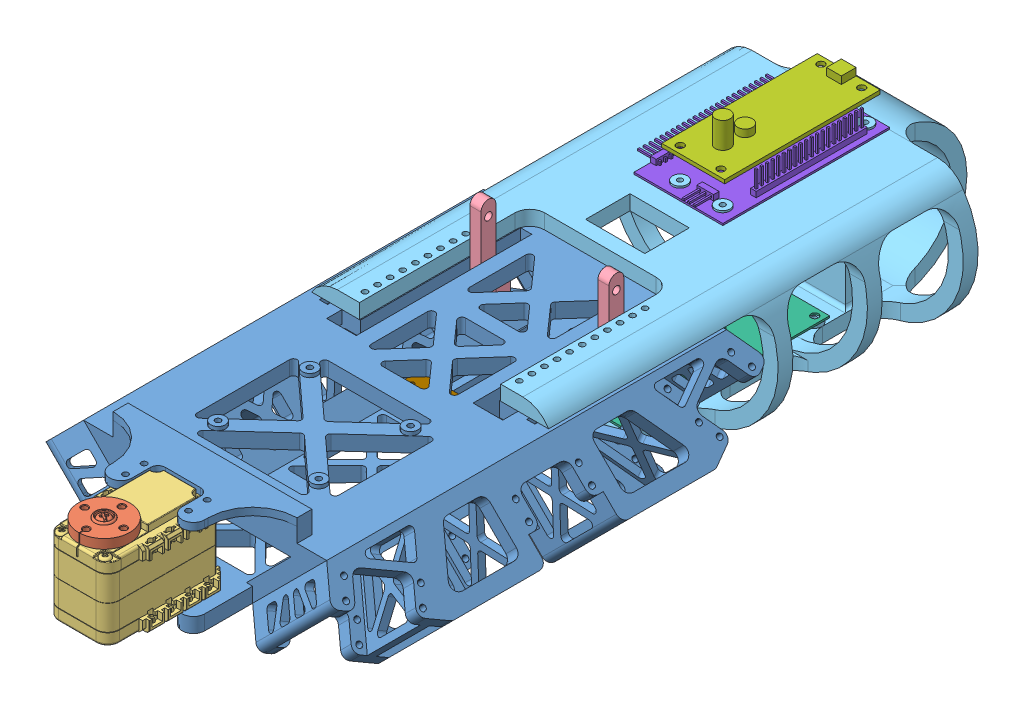
SolidWorks assembly A-Robot-002, configuration Default. Lengths in mm.
Overall size (153.62 88.9 360.89).
11 component instances, 9 part files, 22 mates.
Components (placement in the parent):
- M-Body-001-1: M-Body-001 [Default] at (-27.5626 -3.3241 -51.9175) size (153.62 65.97 203.5)
- A-Act-001-3: A-Act-001 [Default] at (-33.1124 6.4909 112.8079) x (0 1 0) z (1 0 0) size (40.85 50 32)
  - P-Act-002-1: P-Act-002 [Default] at (15.66 50.1246 5.628) x (0 0.99898 0.045152) z (0 0.045152 -0.99898) size (22 14.85 22)
  - P-Act-003-1: P-Act-003 [Default] at (-3.34 38.1246 5.628) x (0 -1 0) z (0 0 -1) size (50 38.01 32)
- M-Body-003-1: M-Body-003 [Default] at (-0.9345 -3.2606 -30.156) x (1 0 0) z (0 -1 0) size (11.11 6.35 38.1)
- M-Body-002-1: M-Body-002 [Default] at (-27.5626 12.5509 -65.8081) x (-1 0 0) z (0 0 -1) size (114.34 65.09 209.55)
- P-Elec-003-2: P-Elec-003 [Default] at (-27.5626 -36.6616 -84.6871) size (41.27 23.02 85.72)
- P-Elec-004-1: P-Elec-004 [Default] at (-24.3876 31.6009 -119.8855) x (0 0 -1) z (1 0 0) size (66.67 12.7 26.99)
- P-Elec-005-1: P-Elec-005 [Default] at (-27.5626 18.9009 -119.0918) size (44.45 10.32 72.23)
- M-Body-004-1: M-Body-004 [Default] at (-27.5626 -6.4991 16.7419) x (-1 0 0) z (0 0 1) size (34.92 6.35 12.7)
- M-Body-003-2: M-Body-003 [Default] at (-54.1907 -3.2606 -23.806) x (-1 0 0) z (0 -1 0) size (11.11 6.35 38.1)
Mates (geometry in assembly coordinates):
- Coincident20: coincident anti-aligned: plane of Thorax-1 through (-9.8277 -12.8491 119.5325) normal (0 1 0); plane of AX12-3/ax12_box-1 through (-40.4845 -12.8491 174.4325) normal (0 -1 0)
- Distance4: distance = 0.7937 mm anti-aligned: plane of AX12-3/ax12_box-1 through (-37.4845 19.4009 133.4325) normal (-1 0 0); plane of Thorax-1 through (-38.2782 18.9009 -51.9175) normal (1 0 0)
- Parallel4: parallel anti-aligned: plane of Thorax-1 through (2.304 -70.1265 -45.5675) normal (-1 0 0); plane of Mounting Hook-1 through (2.2405 -3.2606 -23.806) normal (1 0 0)
- Coincident29: coincident anti-aligned: plane of Thorax-1 through (-3.5058 1.5019 28.763) normal (0 -1 0); plane of Mounting Hook-1 through (-3.4872 1.5019 -23.806) normal (0 1 0)
- Coincident31: coincident anti-aligned: plane of Thorax-1 through (-2.522 1.5019 28.763) normal (1 0 0); plane of Mounting Hook-1 through (-2.522 1.5019 -23.806) normal (-1 0 0)
- Coincident58: coincident anti-aligned: plane of Thorax-1 through (24.5525 12.5509 119.5325) normal (0 1 0); plane of Abdomen New-1 through (-27.5626 12.5509 -65.8081) normal (0 -1 0)
- Coincident59: coincident anti-aligned: plane of Thorax-1 through (-27.5626 -3.3241 -51.9175) normal (1 0 0); plane of Abdomen New-1 through (-27.5626 12.5509 -65.8081) normal (-1 0 0)
- Distance7: distance = 2.3813 mm: plane of Power Supply Chip-2 through (-48.2001 -35.8679 -41.8246) normal (0 0 1); line of Abdomen New-1 through (-6.9251 -36.973 -39.4434) axis (-1 0 0)
- Distance5: distance = 1.5875 mm anti-aligned: plane of Abdomen New-1 through (-48.2001 -38.2491 -154.7081) normal (0 1 0); plane of Power Supply Chip-2 through (-27.5626 -36.6616 -84.6871) normal (0 -1 0)
- Distance6: distance = 25.4 mm anti-aligned: plane of Multiplexer-1 through (-27.5626 18.9009 -119.0918) normal (0 -1 0); plane of opencm-1 through (-24.3876 44.3009 -119.8855) normal (0 1 0)
- Concentric9: concentric aligned: circle of opencm-1; circle of Multiplexer-1
- Parallel10: parallel: line of Multiplexer-1 through (-8.5126 19.6946 -83.373) axis (0 0 -1); plane of opencm-1 through (-10.8939 33.1884 -86.548) normal (1 0 0)
- Coincident66: coincident anti-aligned: plane of Abdomen New-1 through (-27.5626 18.9009 -65.8081) normal (0 1 0); plane of Multiplexer-1 through (-27.5626 18.9009 -119.0918) normal (0 -1 0)
- Coincident68: coincident aligned: plane of M-Body-001-1 through (-57.4292 -70.1265 23.0919) normal (0 0 1); plane of M-Body-002-1 through (23.2374 18.9009 23.0919) normal (0 0 1)
- Coincident69: coincident aligned: plane of Power Supply Chip-2 through (-27.5626 -36.6616 -84.6871) normal (1 0 0); plane of Multiplexer-1 through (-27.5626 18.9009 -119.0918) normal (1 0 0)
- Coincident70: coincident anti-aligned: plane of Abdomen New-1 through (-27.5626 12.5509 -65.8081) normal (-1 0 0); plane of Power Supply Chip-2 through (-27.5626 -36.6616 -84.6871) normal (1 0 0)
- Coincident75: coincident aligned: plane of Abdomen New-1 through (-27.5626 12.5509 -65.8081) normal (-1 0 0); plane of Abdomen Brace Bar-1 through (-27.5626 -6.4991 16.7419) normal (-1 0 0)
- Coincident76: coincident anti-aligned: plane of Abdomen Brace Bar-1 through (-27.5626 -12.8491 16.7419) normal (0 -1 0); plane of Thorax-1 through (-9.8277 -12.8491 119.5325) normal (0 1 0)
- Concentric10: concentric anti-aligned: cylinder of Mounting Hook-1 through (-2.522 31.6644 -26.981) axis (-1 0 0) radius 3.175; cylinder of Mounting Hook-2 through (-52.6032 31.6644 -26.981) axis (1 0 0) radius 3.175
- Coincident78: coincident aligned: plane of Mounting Hook-1 through (-0.9345 -3.2606 -23.806) normal (0 0 1); plane of Mounting Hook-2 through (-54.1907 -3.2606 -23.806) normal (0 0 1)
- Coincident79: coincident anti-aligned: plane of Thorax-1 through (-52.6032 -70.1265 29.6959) normal (-1 0 0); plane of Mounting Hook-2 through (-52.6032 1.5019 -30.156) normal (1 0 0)
- Coincident80: coincident aligned: plane of Abdomen New-1 through (-48.2001 -19.1991 23.0919) normal (0 0 1); plane of Abdomen Brace Bar-1 through (-10.1001 -12.8491 23.0919) normal (0 0 1)
